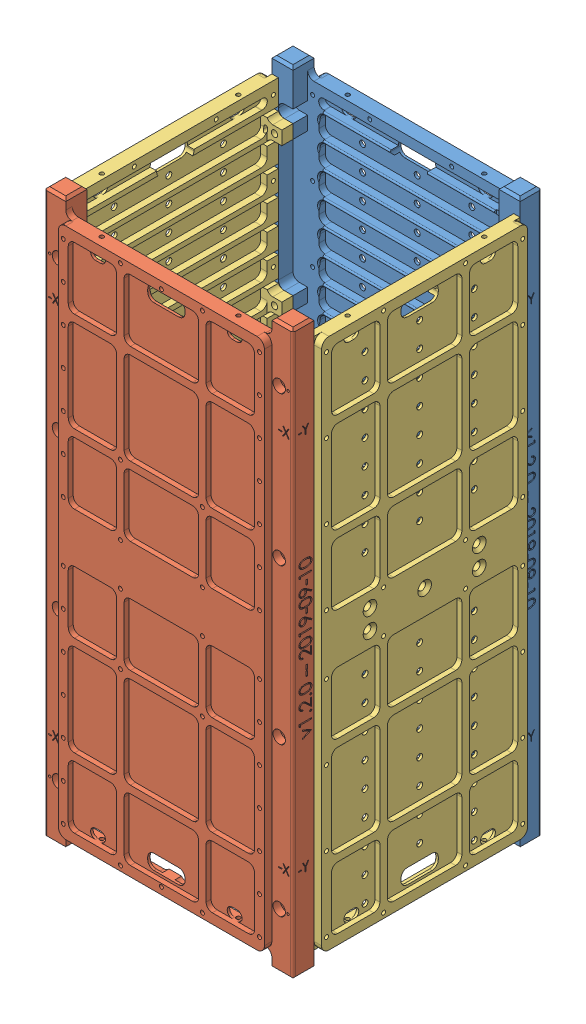
SolidWorks assembly OreSatFramesONLY, configuration Default. Lengths in mm.
Overall size (106 305.38 106).
5 component instances, 3 part files, 0 mates.
Components (placement in the parent):
- FramesONLY.stp-1: FramesONLY.stp [Default] at origin size (106 227 106)
  - Frame_+X.stp-1: Frame_+X.stp [Default] at (0 0 -50) size (100 227 11.5)
  - Frame_-X.stp-1: Frame_-X.stp [Default] at (0 0 50) x (-1 0 0) z (0 0 -1) size (100 227 11.5)
  - Frame_Y.stp-1: Frame_Y.stp [Default] at (-50 0 0) x (0 0 -1) z (1 0 0) size (83 214 11.5)
  - Frame_Y.stp-2: Frame_Y.stp [Default] at (50 0 0) x (0 0 1) z (-1 0 0) size (83 214 11.5)
